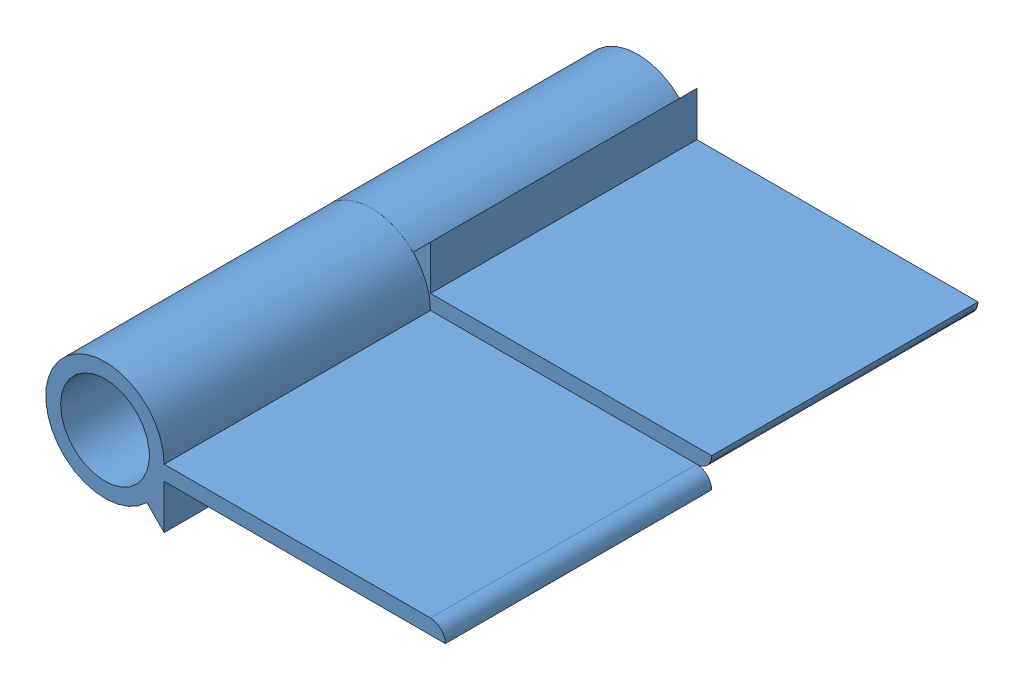
SolidWorks assembly Bisagra, configuration Default. Lengths in mm.
Overall size (54 16 72).
2 component instances, 1 part files, 1 mates.
Components (placement in the parent):
- Bisagra-1: Bisagra [Default] at (4.5212 31.9216 19.0662) size (54 16 36)
- Bisagra-2: Bisagra [Default] at (4.5212 31.9216 91.0662) x (1 0 0) z (0 0 -1) size (54 16 36)
Mates (geometry in assembly coordinates):
- Hinge1: hinge = 3.141593 rad anti-aligned: cylinder of Bisagra-1 through (4.5212 31.9216 55.0662) axis (0 0 -1) radius 8; cylinder of Bisagra-1 through (4.5212 31.9216 55.0662) axis (0 0 1) radius 8; plane of Bisagra-2 through (48.5212 33.9216 55.0662) normal (0 0 1); plane of Bisagra-2 through (48.5212 29.9216 55.0662) normal (0 0 -1); plane of Bisagra-1 through (12.5212 31.9216 55.0662) normal (0 -1 0); plane of Bisagra-2 through (12.5212 31.9216 55.0662) normal (0 1 0)
